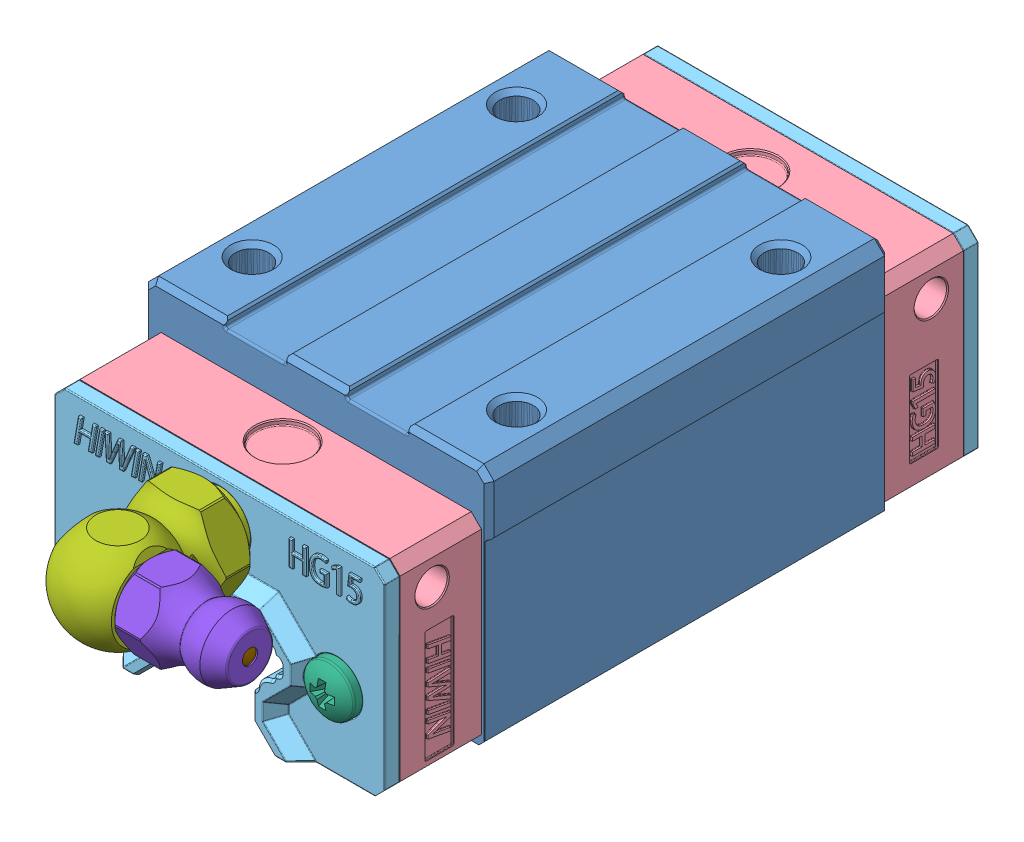
SolidWorks assembly HGH15CACZ, configuration Default. Lengths in mm.
Overall size (34 23.7 74.95).
16 component instances, 10 part files, 33 mates.
Components (placement in the parent):
- HGH15CA Block-1: HGH15CA Block [HGR15R300CE20] at origin size (34 23.7 39.4)
- HGH15CA Retainer-1: HGH15CA Retainer [HGR15R300CE20] at origin size (26 4 55.4)
- HGH15CA Tiny Red-1: HGH15CA Tiny Red [HGR15R300CE20] at origin size (14.2 1 55.4)
- HGH15CA End Cap-1: HGH15CA End Cap [HGR15R300CE20] at origin size (32.5 19.5 8)
- HGH15CA End Cap-2: HGH15CA End Cap [HGR15R300CE20] x (-1 0 0) z (0 0 -1) size (32.5 19.5 8)
- HGR15CA Seal-1: HGR15CA Seal [HGR15R300CE20] at origin size (32.5 19.5 3)
- HGR15CA Seal-2: HGR15CA Seal [HGR15R300CE20] x (-1 0 0) z (0 0 -1) size (32.5 19.5 3)
- pan head cross recess screw_iso-1: pan head cross recess screw_iso [ISO 7045 - M2.5 x 16 - Z - 16C] at (11.5 11.8 30.8) x (0 0 -1) z (0 -1 0) size (18.05 5 5)
- pan head cross recess screw_iso-2: pan head cross recess screw_iso [ISO 7045 - M2.5 x 16 - Z - 16C] at (-11.5 11.8 30.8) x (0 0 -1) z (0 1 0) size (18.05 5 5)
- pan head cross recess screw_iso-3: pan head cross recess screw_iso [ISO 7045 - M2.5 x 16 - Z - 16C] at (11.5 11.8 -30.8) x (0 0 1) z (0 -1 0) size (18.05 5 5)
- pan head cross recess screw_iso-4: pan head cross recess screw_iso [ISO 7045 - M2.5 x 16 - Z - 16C] at (-11.5 11.8 -30.8) x (0 0 1) z (0 1 0) size (18.05 5 5)
- Grease Nipple M8x1.0 H3 Mod-1: Grease Nipple M8x1.0 H3 Mod [Default] at (0 20.05 39.2) x (-1 0 0) z (0 1 0) size (18.25 19.7 10)
  - Grease Nipple M8x1.0 H3 Mod-1: Grease Nipple M8x1.0 H3 Mod [B M8x1.00] at origin size (10.29 15.75 10)
  - Grease Nipple A-1: Grease Nipple A [A M6x0.75H3] at (-10.6548 0 0) x (0 1 0) z (0 0 1) size (8.34 14.3 7)
  - Steel Ball-1: Steel Ball [Ø 2.50] at (-11.85 0 0) size (2.5 2.5 2.5)
  - Brezon M8x1.0 H3 Mod-1: Brezon M8x1.0 H3 Mod [Default] at (0 -14.7 0) x (-1 0 0) z (0 -1 0) size (4.12 4.62 9)
Mates (geometry in assembly coordinates):
- Coincident1: coincident aligned: plane of HGH15CA Block-1 through (0 0 0) normal (0 1 0); plane of HGH15CA Retainer-1 through (0 0 0) normal (0 1 0)
- Coincident2: coincident aligned: plane of HGH15CA Block-1 through (0 0 0) normal (0 0 1); plane of HGH15CA Retainer-1 through (0 0 0) normal (0 0 1)
- Coincident3: coincident aligned: plane of HGH15CA Block-1 through (0 0 0) normal (1 0 0); plane of HGH15CA Retainer-1 through (0 0 0) normal (1 0 0)
- Coincident4: coincident aligned: plane of HGH15CA Block-1 through (0 0 0) normal (0 1 0); plane of HGH15CA Tiny Red-1 through (0 0 0) normal (0 1 0)
- Coincident5: coincident aligned: plane of HGH15CA Block-1 through (0 0 0) normal (0 0 1); plane of HGH15CA Tiny Red-1 through (0 0 0) normal (0 0 1)
- Coincident6: coincident aligned: plane of HGH15CA Block-1 through (0 0 0) normal (1 0 0); plane of HGH15CA Tiny Red-1 through (0 0 0) normal (1 0 0)
- Coincident7: coincident aligned: plane of HGH15CA Block-1 through (0 0 0) normal (0 1 0); plane of HGH15CA End Cap-1 through (0 0 0) normal (0 1 0)
- Coincident8: coincident aligned: plane of HGH15CA Block-1 through (0 0 0) normal (0 0 1); plane of HGH15CA End Cap-1 through (0 0 0) normal (0 0 1)
- Coincident9: coincident aligned: plane of HGH15CA Block-1 through (0 0 0) normal (1 0 0); plane of HGH15CA End Cap-1 through (0 0 0) normal (1 0 0)
- Coincident10: coincident aligned: plane of HGH15CA Block-1 through (0 0 0) normal (0 1 0); plane of HGH15CA End Cap-2 through (0 0 0) normal (0 1 0)
- Coincident11: coincident anti-aligned: plane of HGH15CA Block-1 through (12.9 8.2 -19.7) normal (0 0 -1); plane of HGH15CA End Cap-2 through (-12.9 8.2 -19.7) normal (0 0 1)
- Coincident12: coincident anti-aligned: plane of HGH15CA Block-1 through (0 0 0) normal (1 0 0); plane of HGH15CA End Cap-2 through (0 0 0) normal (-1 0 0)
- Coincident14: coincident aligned: plane of HGH15CA Block-1 through (0 0 0) normal (0 1 0); plane of HGR15CA Seal-1 through (0 0 0) normal (0 1 0)
- Coincident15: coincident aligned: plane of HGH15CA Block-1 through (0 0 0) normal (0 0 1); plane of HGR15CA Seal-1 through (0 0 0) normal (0 0 1)
- Coincident16: coincident aligned: plane of HGH15CA Block-1 through (0 0 0) normal (1 0 0); plane of HGR15CA Seal-1 through (0 0 0) normal (1 0 0)
- Coincident17: coincident aligned: plane of HGH15CA Block-1 through (0 0 0) normal (0 1 0); plane of HGR15CA Seal-2 through (0 0 0) normal (0 1 0)
- Coincident18: coincident anti-aligned: plane of HGH15CA End Cap-2 through (-12.9 8.2 -27.7) normal (0 0 -1); plane of HGR15CA Seal-2 through (5.15 6.4157 -27.7) normal (0 0 1)
- Coincident19: coincident anti-aligned: plane of HGH15CA Block-1 through (0 0 0) normal (1 0 0); plane of HGR15CA Seal-2 through (0 0 0) normal (-1 0 0)
- Concentric1: concentric aligned: cylinder of HGR15CA Seal-1 through (11.5 11.8 28.7) axis (0 0 1) radius 1.5; cylinder of pan head cross recess screw_iso-1 through (11.5 11.8 56.2) axis (0 0 1) radius 1.25
- Concentric2: concentric aligned: cylinder of HGR15CA Seal-1 through (-11.5 11.8 28.7) axis (0 0 1) radius 1.5; cylinder of pan head cross recess screw_iso-2 through (-11.5 11.8 56.2) axis (0 0 1) radius 1.25
- Concentric3: concentric aligned: cylinder of HGR15CA Seal-2 through (11.5 11.8 -28.7) axis (0 0 -1) radius 1.5; cylinder of pan head cross recess screw_iso-3 through (11.5 11.8 -56.2) axis (0 0 -1) radius 1.25
- Concentric4: concentric aligned: cylinder of HGR15CA Seal-2 through (-11.5 11.8 -28.7) axis (0 0 -1) radius 1.5; cylinder of pan head cross recess screw_iso-4 through (-11.5 11.8 -56.2) axis (0 0 -1) radius 1.25
- Coincident20: coincident anti-aligned: plane of HGR15CA Seal-2 through (11.5 11.8 -28.7) normal (0 0 -1); plane of pan head cross recess screw_iso-3 through (10.25 11.8 -28.7) normal (0 0 1)
- Coincident21: coincident anti-aligned: plane of HGR15CA Seal-2 through (-11.5 11.8 -28.7) normal (0 0 -1); plane of pan head cross recess screw_iso-4 through (-10.25 11.8 -28.7) normal (0 0 1)
- Coincident22: coincident anti-aligned: plane of HGR15CA Seal-1 through (11.5 11.8 28.7) normal (0 0 1); plane of pan head cross recess screw_iso-1 through (12.75 11.8 28.7) normal (0 0 -1)
- Coincident23: coincident anti-aligned: plane of HGR15CA Seal-1 through (-11.5 11.8 28.7) normal (0 0 1); plane of pan head cross recess screw_iso-2 through (-12.75 11.8 28.7) normal (0 0 -1)
- Parallel1: parallel anti-aligned: plane of HGH15CA Block-1 through (0 0 0) normal (0 1 0); plane of pan head cross recess screw_iso-1 through (11.5 11.8 30.8) normal (0 -1 0)
- Parallel2: parallel aligned: plane of HGH15CA Block-1 through (0 0 0) normal (0 1 0); plane of pan head cross recess screw_iso-2 through (-11.5 11.8 30.8) normal (0 1 0)
- Parallel3: parallel anti-aligned: plane of HGH15CA Block-1 through (0 0 0) normal (0 1 0); plane of pan head cross recess screw_iso-3 through (11.5 11.8 -30.8) normal (0 -1 0)
- Parallel4: parallel aligned: plane of HGH15CA Block-1 through (0 0 0) normal (0 1 0); plane of pan head cross recess screw_iso-4 through (-11.5 11.8 -30.8) normal (0 1 0)
- Concentric5: concentric anti-aligned: cylinder of HGR15CA Seal-1 through (0 20.05 28.7) axis (0 0 1) radius 2.25; cylinder of Grease Nipple M8x1.0 H3 Mod-1/Brezon M8x1.0 H3 Mod-1 through (0 20.05 33.5) axis (0 0 -1) radius 2
- Coincident24: coincident anti-aligned: plane of HGR15CA Seal-1 through (0 20.05 28.7) normal (0 0 1); plane of Grease Nipple M8x1.0 H3 Mod-1/Grease Nipple M8x1.0 H3 Mod-1 through (-2.75 20.05 28.7) normal (0 0 -1)
- Parallel6: parallel aligned: plane of HGH15CA Block-1 through (0 0 0) normal (0 1 0); plane of Grease Nipple M8x1.0 H3 Mod-1/Grease Nipple M8x1.0 H3 Mod-1 through (0 20.05 39.2) normal (0 1 0)
